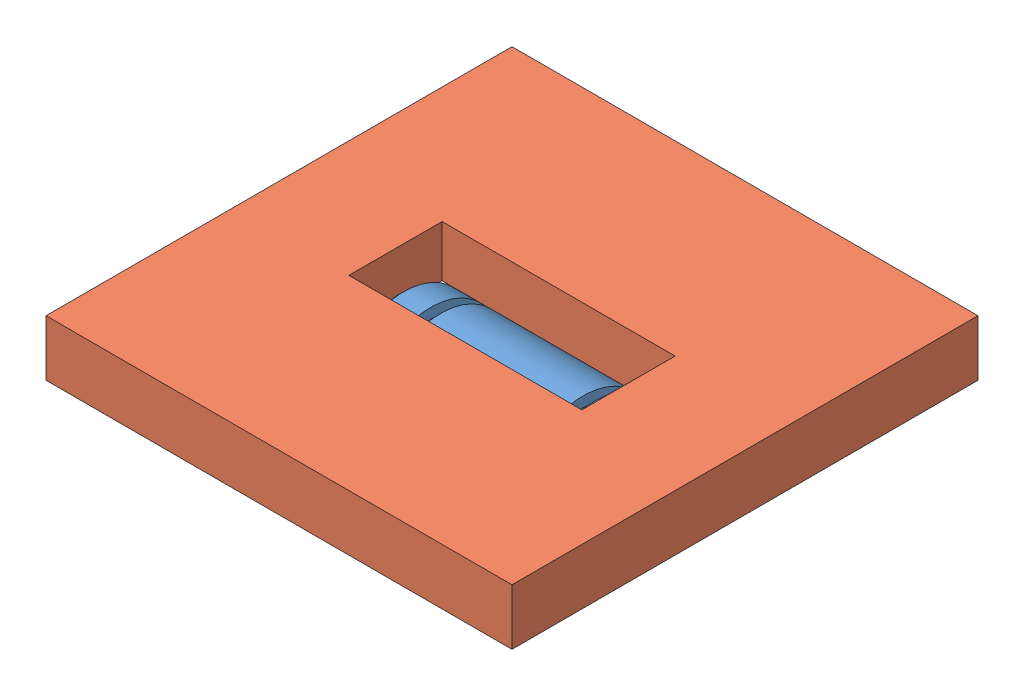
SolidWorks assembly zzz_mate linear bearing, configuration Default. Lengths in mm.
Overall size (50 18.61 50).
2 component instances, 2 part files, 5 mates.
Components (placement in the parent):
- x_LM8UU-1: x_LM8UU [Default] at origin size (24 15 15)
- Part3^zzz_mate linear bearing-1: Part3^zzz_mate linear bearing [Default] at (0 11.1066 0) x (-1 0 0) z (0 0 1) size (50 6 50) (virtual)
Mates (geometry in assembly coordinates):
- Coincident1: coordinate: point of x_LM8UU-1; point of assembly
- Parallel1: parallel anti-aligned: plane of Part3^zzz_mate linear bearing-1 through (0 5.1066 0) normal (0 -1 0); plane of assembly through (0 0 0) normal (0 1 0)
- Tangent1: tangent anti-aligned: cylinder of x_LM8UU-1 through (-45.6895 0 0) axis (-1 0 0) radius 7.5; plane of Part3^zzz_mate linear bearing-1 through (12.5 5.6066 -5) normal (0 -0.707107 0.707107)
- Tangent2: tangent anti-aligned: cylinder of x_LM8UU-1 through (-45.6895 0 0) axis (-1 0 0) radius 7.5; plane of Part3^zzz_mate linear bearing-1 through (12.5 5.6066 5) normal (0 -0.707107 -0.707107)
- Width1: width anti-aligned: plane of Part3^zzz_mate linear bearing-1 through (-12.5 11.1066 -5) normal (1 0 0); plane of Part3^zzz_mate linear bearing-1 through (12.5 11.1066 -5) normal (-1 0 0); plane of x_LM8UU-1 through (-12 0 0) normal (-1 0 0); plane of x_LM8UU-1 through (12 0 0) normal (1 0 0)
